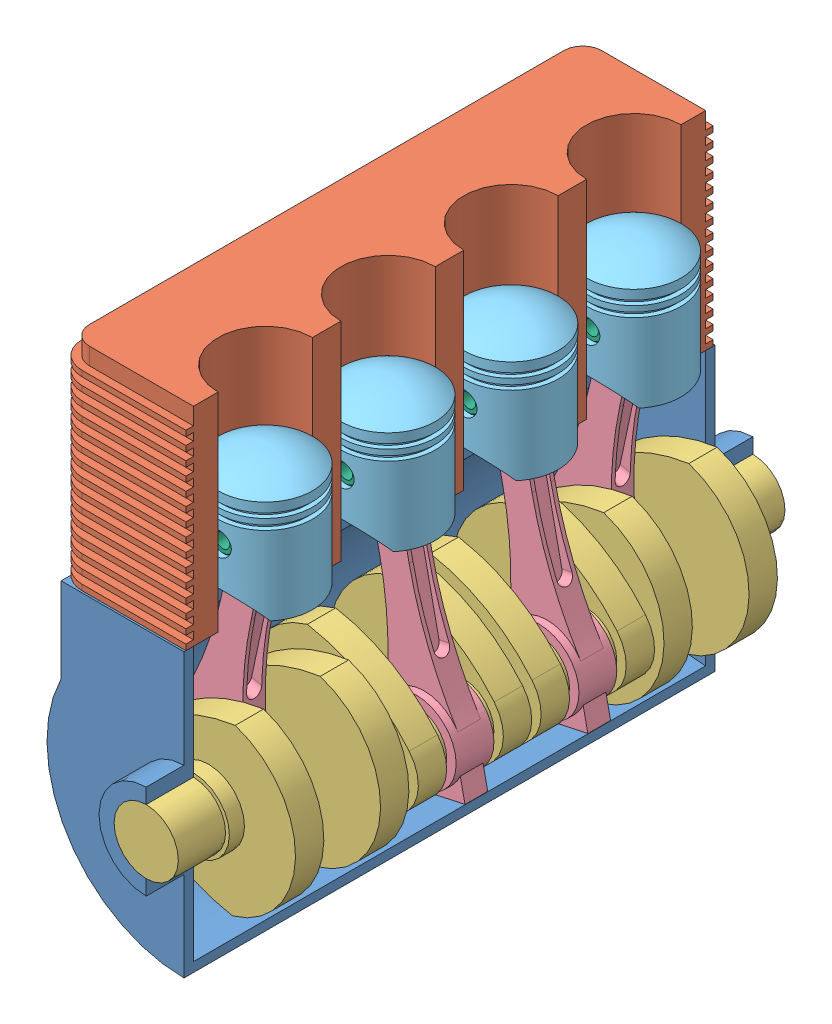
SolidWorks assembly Engine 4  Cylinder, configuration Default. Lengths in mm.
Overall size (123.1 259.5 321).
15 component instances, 6 part files, 29 mates.
Components (placement in the parent):
- Lower Block-1: Lower Block [Default] at (106.862 148.4133 424.3107) size (72.5 149.5 321)
- Upper Block-1: Upper Block [Default] at (106.862 225.4133 419.3107) x (0 0 -1) z (1 0 0) size (279 110 69)
- Crankshaft1-2: Crankshaft1 [Default] at (106.862 148.4133 148.3107) x (0.015408 0.999881 0) z (0 0 1) size (88 92 321)
- Connecting Rod-1: Connecting Rod [Default] at (81.865 148.7985 381.3107) x (0.978063 -0.208309 0) z (0 0 1) size (42 160.15 20)
- Piston-1: Piston [Default] at (106.862 235.6661 381.3107) size (50 64.17 50)
- Piston Pin-1: Piston Pin [Default] at (106.862 266.1661 381.3107) size (12.5 12.5 45)
- Connecting Rod-2: Connecting Rod [Default] at (81.865 148.7985 186.3107) x (-0.978063 0.208309 0) z (0 0 -1) size (42 160.15 20)
- Piston-2: Piston [Default] at (106.862 235.6661 186.3107) x (-1 0 0) z (0 0 -1) size (50 64.17 50)
- Piston Pin-2: Piston Pin [Default] at (106.862 266.1661 186.3107) x (-0.173648 0.984808 0) z (0 0 -1) size (12.5 12.5 45)
- Connecting Rod-4: Connecting Rod [Default] at (131.859 148.0281 251.3107) x (-0.978063 -0.208309 0) z (0 0 -1) size (42 160.15 20)
- Piston-4: Piston [Default] at (106.862 234.8957 251.3107) x (-1 0 0) z (0 0 -1) size (50 64.17 50)
- Piston Pin-4: Piston Pin [Default] at (106.862 265.3957 251.3107) x (-0.34202 0.939693 0) z (0 0 -1) size (12.5 12.5 45)
- Piston Pin-10: Piston Pin [Default] at (106.862 265.3957 316.3107) x (0.987351 0.158553 0) z (0 0 1) size (12.5 12.5 45)
- Piston-10: Piston [Default] at (106.862 234.8957 316.3107) size (50 64.17 50)
- Connecting Rod-10: Connecting Rod [Default] at (131.859 148.0281 316.3107) x (0.978063 0.208309 0) z (0 0 1) size (42 160.15 20)
Mates (geometry in assembly coordinates):
- Coincident2: coincident: plane of assembly; plane of assembly; plane of Lower Block-1 through (106.862 173.4133 419.3107) normal (1 0 0); plane of Upper Block-1 through (106.862 335.4133 419.3107) normal (1 0 0)
- Coincident3: coincident: plane of assembly; plane of assembly; plane of Lower Block-1 through (106.862 225.4133 419.3107) normal (0 1 0); plane of Upper Block-1 through (106.862 225.4133 381.3107) normal (0 -1 0)
- Width1: width: plane of assembly; plane of assembly; plane of assembly; plane of assembly; plane of Lower Block-1 through (106.862 148.4133 424.3107) normal (0 0 1); plane of Lower Block-1 through (106.862 148.4133 143.3107) normal (0 0 -1); plane of Upper Block-1 through (106.862 335.4133 419.3107) normal (0 0 1); plane of Upper Block-1 through (106.862 335.4133 148.3107) normal (0 0 -1)
- Concentric1: concentric: cylinder of assembly; cylinder of assembly; cylinder of Lower Block-1 through (106.862 148.4133 419.3107) axis (0 0 1) radius 17; cylinder of Crankshaft1-2 through (106.862 148.4133 444.3107) axis (0 0 -1) radius 17
- Coincident4: coincident: plane of assembly; plane of assembly; plane of Lower Block-1 through (106.862 148.4133 444.3107) normal (0 0 1); plane of Crankshaft1-2 through (106.862 148.4133 444.3107) normal (0 0 1)
- Concentric3: concentric: cylinder of assembly; cylinder of assembly; cylinder of Piston-1 through (106.862 266.1661 356.3107) axis (0 0 1) radius 6.25; cylinder of Piston Pin-1 through (106.862 266.1661 403.8107) axis (0 0 -1) radius 6.25
- Width2: width: plane of assembly; plane of assembly; plane of assembly; plane of assembly; plane of Piston-1 through (106.862 266.1661 369.3107) normal (0 0 1); plane of Piston-1 through (106.862 266.1661 393.3107) normal (0 0 -1); plane of Piston Pin-1 through (106.862 266.1661 358.8107) normal (0 0 -1); plane of Piston Pin-1 through (106.862 266.1661 403.8107) normal (0 0 1)
- Concentric4: concentric: cylinder of assembly; cylinder of assembly; cylinder of Connecting Rod-1 through (106.862 266.1661 391.3107) axis (0 0 -1) radius 6.25; cylinder of Piston Pin-1 through (106.862 266.1661 403.8107) axis (0 0 -1) radius 6.25
- Width3: width: plane of assembly; plane of assembly; plane of assembly; plane of assembly; plane of Piston-1 through (106.862 266.1661 393.3107) normal (0 0 -1); plane of Piston-1 through (106.862 266.1661 369.3107) normal (0 0 1); plane of Connecting Rod-1 through (81.865 148.7985 391.3107) normal (0 0 1); plane of Connecting Rod-1 through (81.865 148.7985 371.3107) normal (0 0 -1)
- Concentric5: concentric: cylinder of assembly; cylinder of assembly; cylinder of Crankshaft1-2 through (81.865 148.7985 381.3107) axis (0 0 1) radius 16; cylinder of Connecting Rod-1 through (81.865 148.7985 391.3107) axis (0 0 -1) radius 16
- Concentric6: concentric: cylinder of assembly; cylinder of assembly; cylinder of Upper Block-1 through (106.862 335.4133 381.3107) axis (0 -1 0) radius 25; cylinder of Piston-1 through (106.862 298.1661 381.3107) axis (0 1 0) radius 25
- Concentric7: concentric: cylinder of assembly; cylinder of assembly; cylinder of Piston-2 through (106.862 266.1661 211.3107) axis (0 0 -1) radius 6.25; cylinder of Piston Pin-2 through (106.862 266.1661 163.8107) axis (0 0 1) radius 6.25
- Width4: width: plane of assembly; plane of assembly; plane of assembly; plane of assembly; plane of Piston-2 through (106.862 266.1661 198.3107) normal (0 0 -1); plane of Piston-2 through (106.862 266.1661 174.3107) normal (0 0 1); plane of Piston Pin-2 through (106.862 266.1661 208.8107) normal (0 0 1); plane of Piston Pin-2 through (106.862 266.1661 163.8107) normal (0 0 -1)
- Concentric8: concentric: cylinder of assembly; cylinder of assembly; cylinder of Connecting Rod-2 through (106.862 266.1661 176.3107) axis (0 0 1) radius 6.25; cylinder of Piston Pin-2 through (106.862 266.1661 163.8107) axis (0 0 1) radius 6.25
- Width5: width: plane of assembly; plane of assembly; plane of assembly; plane of assembly; plane of Piston-2 through (106.862 266.1661 174.3107) normal (0 0 1); plane of Piston-2 through (106.862 266.1661 198.3107) normal (0 0 -1); plane of Connecting Rod-2 through (81.865 148.7985 176.3107) normal (0 0 -1); plane of Connecting Rod-2 through (81.865 148.7985 196.3107) normal (0 0 1)
- Concentric9: concentric: cylinder of assembly; cylinder of assembly; cylinder of Crankshaft1-2 through (81.865 148.7985 186.3107) axis (0 0 -1) radius 16; cylinder of Connecting Rod-2 through (81.865 148.7985 176.3107) axis (0 0 1) radius 16
- Concentric10: concentric: cylinder of assembly; cylinder of assembly; cylinder of Upper Block-1 through (106.862 335.4133 186.3107) axis (0 -1 0) radius 25; cylinder of Piston-2 through (106.862 298.1661 186.3107) axis (0 1 0) radius 25
- Concentric13: concentric: cylinder of assembly; cylinder of assembly; cylinder of Piston-4 through (106.862 265.3957 276.3107) axis (0 0 -1) radius 6.25; cylinder of Piston Pin-4 through (106.862 265.3957 228.8107) axis (0 0 1) radius 6.25
- Width8: width: plane of assembly; plane of assembly; plane of assembly; plane of assembly; plane of Piston-4 through (106.862 265.3957 263.3107) normal (0 0 -1); plane of Piston-4 through (106.862 265.3957 239.3107) normal (0 0 1); plane of Piston Pin-4 through (106.862 265.3957 273.8107) normal (0 0 1); plane of Piston Pin-4 through (106.862 265.3957 228.8107) normal (0 0 -1)
- Concentric14: concentric: cylinder of assembly; cylinder of assembly; cylinder of Connecting Rod-4 through (106.862 265.3957 241.3107) axis (0 0 1) radius 6.25; cylinder of Piston Pin-4 through (106.862 265.3957 228.8107) axis (0 0 1) radius 6.25
- Width9: width: plane of assembly; plane of assembly; plane of assembly; plane of assembly; plane of Piston-4 through (106.862 265.3957 239.3107) normal (0 0 1); plane of Piston-4 through (106.862 265.3957 263.3107) normal (0 0 -1); plane of Connecting Rod-4 through (131.859 148.0281 241.3107) normal (0 0 -1); plane of Connecting Rod-4 through (131.859 148.0281 261.3107) normal (0 0 1)
- Concentric15: concentric: cylinder of assembly; cylinder of assembly; cylinder of Crankshaft1-2 through (131.859 148.0281 266.3107) axis (0 0 -1) radius 16; cylinder of Connecting Rod-4 through (131.859 148.0281 241.3107) axis (0 0 1) radius 16
- Concentric16: concentric: cylinder of assembly; cylinder of assembly; cylinder of Upper Block-1 through (106.862 335.4133 251.3107) axis (0 -1 0) radius 25; cylinder of Piston-4 through (106.862 297.3957 251.3107) axis (0 1 0) radius 25
- Concentric32: concentric: cylinder of assembly; cylinder of assembly; cylinder of Piston Pin-10 through (106.862 265.3957 338.8107) axis (0 0 -1) radius 6.25; cylinder of Piston-10 through (106.862 265.3957 291.3107) axis (0 0 1) radius 6.25
- Width20: width: plane of assembly; plane of assembly; plane of assembly; plane of assembly; plane of Piston-10 through (106.862 265.3957 304.3107) normal (0 0 1); plane of Piston-10 through (106.862 265.3957 328.3107) normal (0 0 -1); plane of Piston Pin-10 through (106.862 265.3957 293.8107) normal (0 0 -1); plane of Piston Pin-10 through (106.862 265.3957 338.8107) normal (0 0 1)
- Concentric33: concentric: cylinder of assembly; cylinder of assembly; cylinder of Piston Pin-10 through (106.862 265.3957 338.8107) axis (0 0 -1) radius 6.25; cylinder of Connecting Rod-10 through (106.862 265.3957 326.3107) axis (0 0 -1) radius 6.25
- Width21: width: plane of assembly; plane of assembly; plane of assembly; plane of assembly; plane of Piston-10 through (106.862 265.3957 328.3107) normal (0 0 -1); plane of Piston-10 through (106.862 265.3957 304.3107) normal (0 0 1); plane of Connecting Rod-10 through (131.859 148.0281 326.3107) normal (0 0 1); plane of Connecting Rod-10 through (131.859 148.0281 306.3107) normal (0 0 -1)
- Concentric34: concentric: cylinder of assembly; cylinder of assembly; cylinder of Crankshaft1-2 through (131.859 148.0281 301.3107) axis (0 0 1) radius 16; cylinder of Connecting Rod-10 through (131.859 148.0281 326.3107) axis (0 0 -1) radius 16
- Concentric35: concentric: cylinder of assembly; cylinder of assembly; cylinder of Upper Block-1 through (106.862 335.4133 316.3107) axis (0 -1 0) radius 25; cylinder of Piston-10 through (106.862 297.3957 316.3107) axis (0 1 0) radius 25
